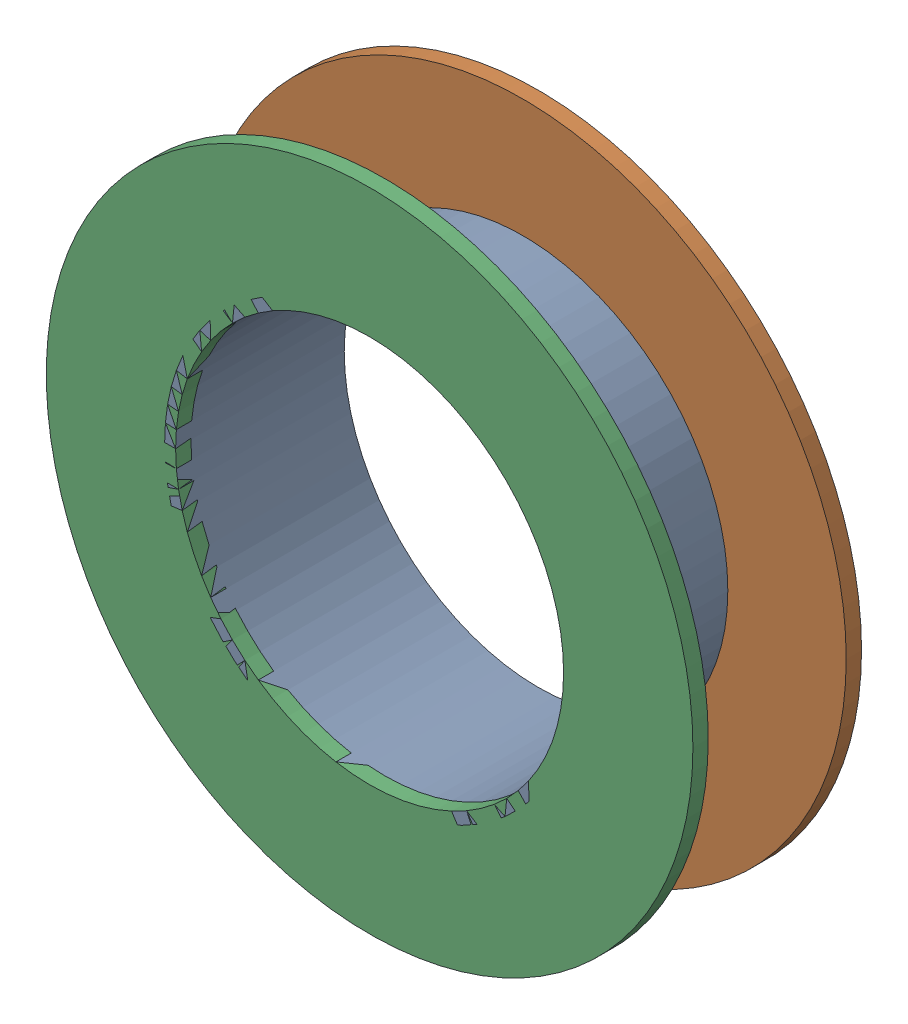
SolidWorks assembly Pad UART-4(20.62mm,43.4mm) on Multi-Layer, configuration Predeterminado. Lengths in mm.
Overall size (1.5 1.5 0.39).
6 component instances, 2 part files, 0 mates.
Components (placement in the parent):
- Pad Hole-1-1: Pad Hole-1 [Predeterminado] at (20.62 43.4 -0.4013) size (0.95 0.95 0.39)
  - Pad Hole-Part-1-1-1: Pad Hole-Part-1-1 [Predeterminado] at origin size (0.95 0.95 0.39)
- Top Layer-1-1: Top Layer-1 [Predeterminado] at (20.62 43.4 -0.4013) size (1.5 1.5 0.04)
  - Top Layer-Part-1-1-1: Top Layer-Part-1-1 [Predeterminado] at origin size (1.5 1.5 0.04)
- Top Layer-1-2: Top Layer-1 [Predeterminado] at (20.62 43.4 -0.0457) size (1.5 1.5 0.04)
  - Top Layer-Part-1-1-1: Top Layer-Part-1-1 [Predeterminado] at origin size (1.5 1.5 0.04)
